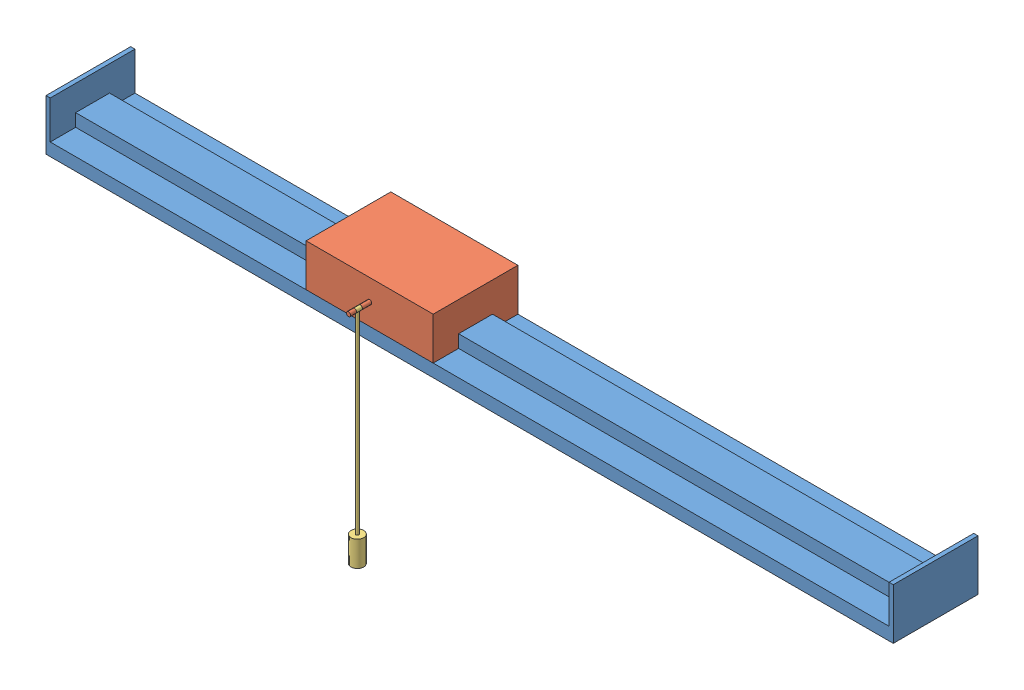
SolidWorks assembly Assem2, configuration Default. Lengths in mm.
Overall size (1000 285 125).
3 component instances, 3 part files, 4 mates.
Components (placement in the parent):
- Part2-1: Part2 [Default] at (881.4256 466.9726 795.4744) size (1000 60 100)
- Part1-1: Part1 [Default] at (338.3945 474.4726 795.4744) size (150 50 125)
- Part3-1: Part3 [Default] at (223.5025 407.7723 703.5519) size (15 262.5 15)
Mates (geometry in assembly coordinates):
- Coincident4: coincident: plane of Part2-1 through (-118.5744 466.9726 775.4744) normal (0 0 -1); plane of Part1-1 through (188.3945 474.4726 775.4744) normal (0 0 1)
- Coincident3: coincident: plane of Part2-1 through (-118.5744 474.4726 795.4744) normal (0 1 0); plane of Part1-1 through (188.3945 474.4726 815.4744) normal (0 -1 0)
- Concentric1: concentric: cylinder of Part1-1 through (263.3945 484.4726 856.4744) axis (0 0 1) radius 1.7339; cylinder of Part3-1 through (263.3945 484.4726 856.4744) axis (0 0 1) radius 1.7339
- Coincident5: coincident: plane of Part1-1 through (263.3945 484.4726 856.4744) normal (0 0 1); plane of Part3-1 through (263.3945 484.4726 856.4744) normal (0 0 -1)
